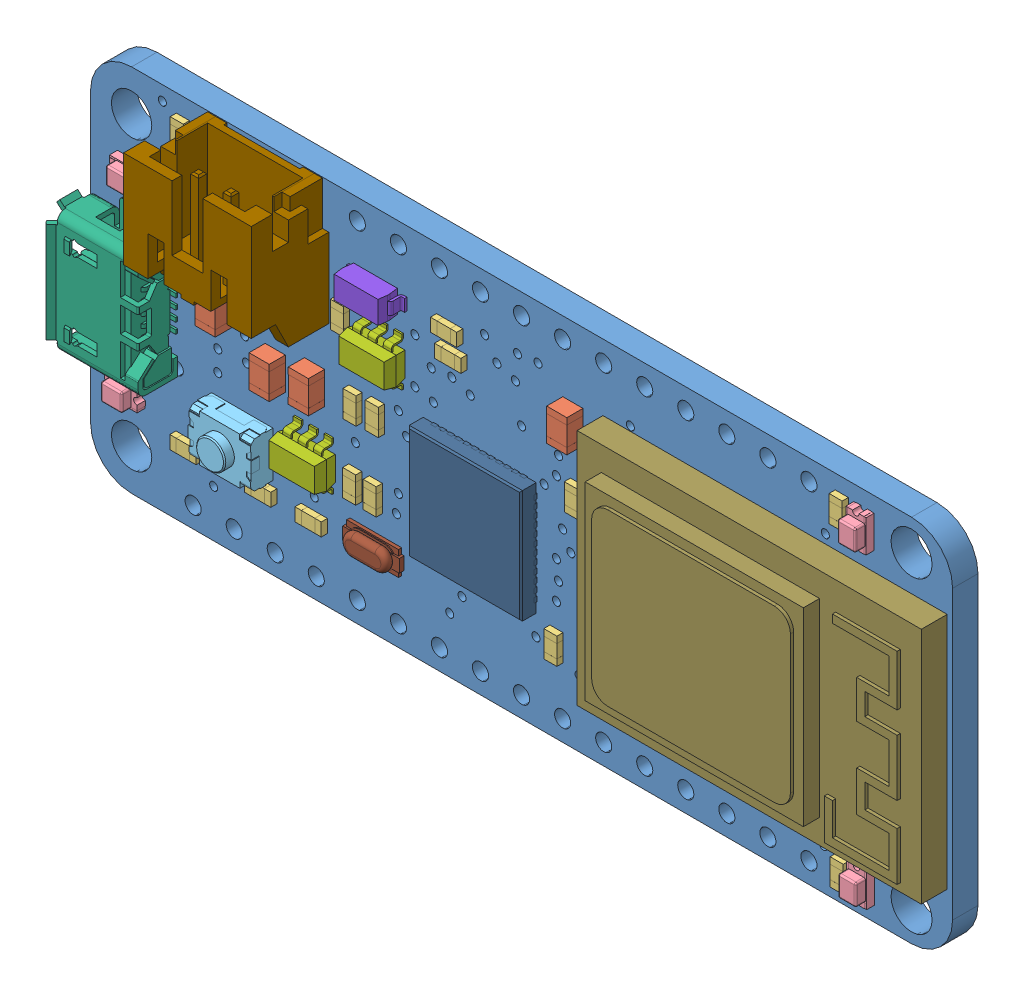
SolidWorks assembly 3010 Adafruit Feather M0 WiFi.step, configuration Default. Lengths in mm.
Overall size (53.54 22.86 6.37).
34 component instances, 12 part files, 0 mates.
Components (placement in the parent):
- PCB Component.step-1: PCB Component.step [Default] at origin size (53.54 22.86 6.37)
  - Board.step-1: Board.step [Default] at origin size (53.34 22.86 1.57)
  - 10uF.step-1: 10uF.step [Default] at (8.088 12.959 1.57) x (0 1 0) z (0 0 1) size (2 1.25 1)
  - 10uF.step-2: 10uF.step [Default] at (13.858 11.624 1.57) x (0 -1 0) z (0 0 1) size (2 1.25 1)
  - 10uF.step-3: 10uF.step [Default] at (11.43 11.176 1.57) x (0 -1 0) z (0 0 1) size (2 1.25 1)
  - 10uF.step-4: 10uF.step [Default] at (29.845 17.526 1.57) x (0 1 0) z (0 0 1) size (2 1.25 1)
  - 1k.step-1: 1k.step [Default] at (16.4 11.735 1.57) x (0 1 0) z (0 0 1) size (1.62 0.81 0.38)
  - 1k.step-2: 1k.step [Default] at (10.719 4.345 1.57) size (1.62 0.81 0.38)
  - 1k.step-3: 1k.step [Default] at (5.715 20.955 1.57) x (0 -1 0) z (0 0 1) size (1.62 0.81 0.38)
  - 1k.step-4: 1k.step [Default] at (6.096 4.318 1.57) size (1.62 0.81 0.38)
  - 1k.step-5: 1k.step [Default] at (13.843 4.318 1.57) x (-1 0 0) z (0 0 1) size (1.62 0.81 0.38)
  - 1k.step-6: 1k.step [Default] at (22.225 18.669 1.57) size (1.62 0.81 0.38)
  - 1k.step-7: 1k.step [Default] at (22.479 17.399 1.57) x (-1 0 0) z (0 0 1) size (1.62 0.81 0.38)
  - 1k.step-8: 1k.step [Default] at (17.78 11.811 1.57) x (0 1 0) z (0 0 1) size (1.62 0.81 0.38)
  - 1k.step-9: 1k.step [Default] at (17.653 7.493 1.57) x (0 1 0) z (0 0 1) size (1.62 0.81 0.38)
  - 1k.step-10: 1k.step [Default] at (16.383 7.493 1.57) x (0 1 0) z (0 0 1) size (1.62 0.81 0.38)
  - 1k.step-11: 1k.step [Default] at (15.621 16.129 1.57) x (0 1 0) z (0 0 1) size (1.62 0.81 0.38)
  - 1k.step-12: 1k.step [Default] at (28.829 5.08 1.57) x (0 -1 0) z (0 0 1) size (1.62 0.81 0.38)
  - 1k.step-13: 1k.step [Default] at (30.099 13.589 1.57) x (0 1 0) z (0 0 1) size (1.62 0.81 0.38)
  - 1k.step-14: 1k.step [Default] at (46.482 21.146 1.57) x (0 1 0) z (0 0 1) size (1.62 0.81 0.38)
  - 1k.step-15: 1k.step [Default] at (46.546 1.714 1.57) x (0 -1 0) z (0 0 1) size (1.62 0.81 0.38)
  - GREEN.step-1: GREEN.step [Default] at (2.645 17.359 1.57) x (0 1 0) z (0 0 1) size (1.25 2.02 1.1)
  - GREEN.step-2: GREEN.step [Default] at (2.413 5.588 1.57) x (0 -1 0) z (0 0 1) size (1.25 2.02 1.1)
  - GREEN.step-3: GREEN.step [Default] at (47.879 1.905 1.57) x (-1 0 0) z (0 0 1) size (1.25 2.02 1.1)
  - GREEN.step-4: GREEN.step [Default] at (47.879 20.955 1.57) size (1.25 2.02 1.1)
  - SPST_TACT-KMR2.step-1: SPST_TACT-KMR2.step [Default] at (9.398 6.477 1.57) x (-1 0 0) z (0 0 1) size (5 2.9 2)
  - microUSB.step-1: microUSB.step [Default] at (4.445 11.43 1.57) x (0 -1 0) z (0 0 1) size (8.8 5.6 3.05)
  - MCP73831T-2ACI_OT.step-1: MCP73831T-2ACI_OT.step [Default] at (18.161 15.494 1.57) x (-1 0 0) z (0 0 1) size (3 3 1.4)
  - MCP73831T-2ACI_OT.step-2: MCP73831T-2ACI_OT.step [Default] at (13.843 7.747 1.57) x (-1 0 0) z (0 0 1) size (3 3 1.4)
  - MBR120.step-1: MBR120.step [Default] at (17.78 18.669 1.57) x (-1 0 0) z (0 0 1) size (3.6 1.4 1.35)
  - JSTPH.step-1: JSTPH.step [Default] at (10.795 19.304 1.57) size (7.9 8.6 4.8)
  - ATSAMD21G18_QFN.step-1: ATSAMD21G18_QFN.step [Default] at (24.13 9.652 1.57) size (7 7 1)
  - 32.768.step-1: 32.768.step [Default] at (17.653 4.699 1.57) size (3.5 1.5 0.8)
  - ATWINC1500_MR210PA.step-1: ATWINC1500_MR210PA.step [Default] at (39.37 11.176 1.57) x (0 -1 0) z (0 0 1) size (14.73 21.3 2.8)
